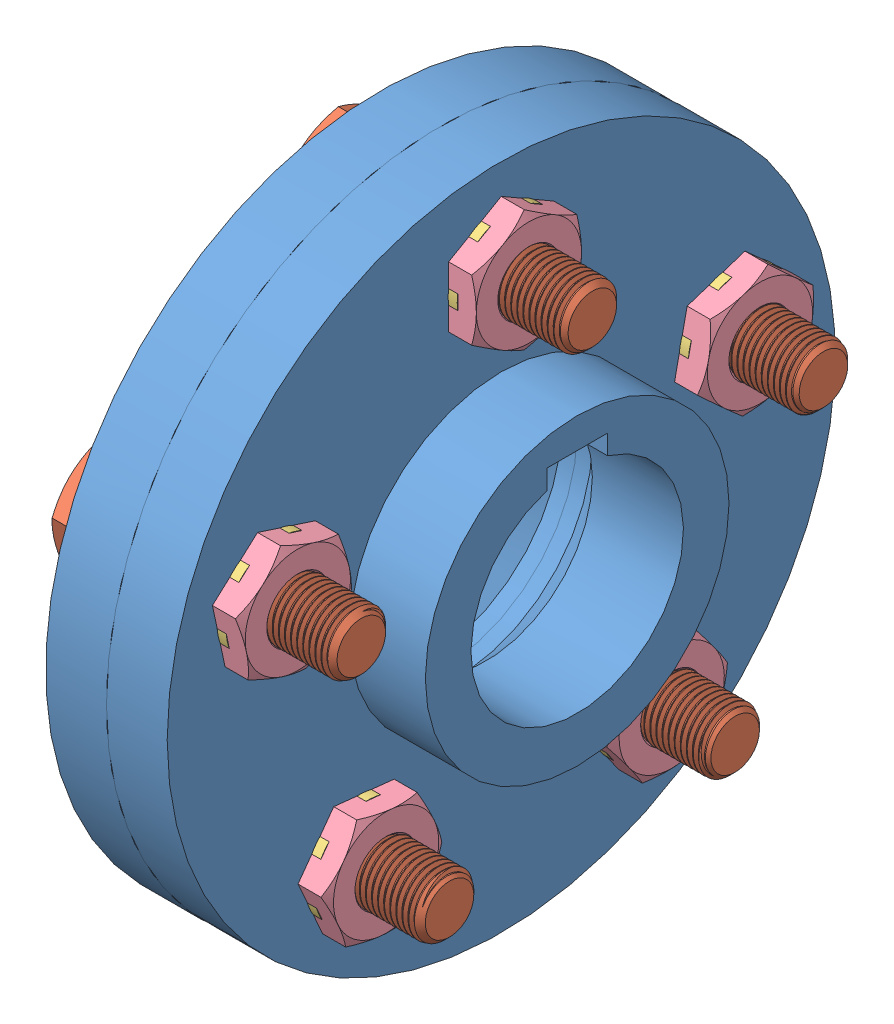
SolidWorks assembly Montaj1, configuration Varsayılan. Lengths in mm.
Overall size (95.08 220 220).
17 component instances, 4 part files, 7 mates.
Components (placement in the parent):
- flange-1: flange [Default] at origin size (45 220 220)
- flange-4: flange [Default] at (-30 0 0) x (-1 0 0) z (0 0 -1) size (45 220 220)
- m20b-1: m20b [Default] at (-35 80 0) x (0 0.448057 0.894005) z (0 -0.894005 0.448057) size (40 84.08 34.64)
- m20w-1: m20w [Default] at (5 80 0) x (0 0.381849 -0.924225) z (0 -0.924225 -0.381849) size (35 3 35)
- m20n-1: m20n [Default] at (6.1117 80 0) x (0 1 0) z (0 0 1) size (40 16 34.64)
- m20n-2: m20n [Default] at (6.1117 24.7214 -76.0845) x (0 0.309017 -0.951057) z (0 0.951057 0.309017) size (40 16 34.64)
- m20n-3: m20n [Default] at (6.1117 -64.7214 -47.0228) x (0 -0.809017 -0.587785) z (0 0.587785 -0.809017) size (40 16 34.64)
- m20n-4: m20n [Default] at (6.1117 -64.7214 47.0228) x (0 -0.809017 0.587785) z (0 -0.587785 -0.809017) size (40 16 34.64)
- m20n-5: m20n [Default] at (6.1117 24.7214 76.0845) x (0 0.309017 0.951057) z (0 -0.951057 0.309017) size (40 16 34.64)
- m20b-2: m20b [Default] at (-35 24.7214 -76.0845) x (0 0.988706 -0.149865) z (0 0.149865 0.988706) size (40 84.08 34.64)
- m20b-3: m20b [Default] at (-35 -64.7214 -47.0228) x (0 0.162997 -0.986627) z (0 0.986627 0.162997) size (40 84.08 34.64)
- m20b-4: m20b [Default] at (-35 -64.7214 47.0228) x (0 -0.887969 -0.459904) z (0 0.459904 -0.887969) size (40 84.08 34.64)
- m20b-5: m20b [Default] at (-35 24.7214 76.0845) x (0 -0.711792 0.70239) z (0 -0.70239 -0.711792) size (40 84.08 34.64)
- m20w-2: m20w [Default] at (5 24.7214 -76.0845) x (0 -0.760992 -0.648761) z (0 -0.648761 0.760992) size (35 3 35)
- m20w-3: m20w [Default] at (5 -64.7214 -47.0228) x (0 -0.852168 0.523268) z (0 0.523268 0.852168) size (35 3 35)
- m20w-4: m20w [Default] at (5 -64.7214 47.0228) x (0 0.234323 0.972159) z (0 0.972159 -0.234323) size (35 3 35)
- m20w-5: m20w [Default] at (5 24.7214 76.0845) x (0 0.996988 0.077559) z (0 0.077559 -0.996988) size (35 3 35)
Mates (geometry in assembly coordinates):
- Eş Merkezli5: concentric anti-aligned: cylinder of flange-1 through (0 0 0) axis (-1 0 0) radius 35; cylinder of flange-4 through (-30 0 0) axis (1 0 0) radius 35
- Çakışık5: coincident anti-aligned: plane of flange-1 through (-15 110 0) normal (-1 0 0); plane of flange-4 through (-15 110 0) normal (1 0 0)
- Çakışık6: coincident anti-aligned: line of flange-1 through (-6.2311 40 10) axis (1 0 0); line of flange-4 through (-23.7689 40 10) axis (-1 0 0)
- Eş Merkezli8: concentric anti-aligned: circle of flange-4; circle of m20b-1
- Çakışık7: coincident anti-aligned: plane of flange-4 through (-35 50 0) normal (-1 0 0); plane of m20b-1 through (-35 80 0) normal (1 0 0)
- Çakışık8: coincident aligned: circle of flange-1; circle of m20w-1
- Eş Merkezli9: concentric anti-aligned: circle of m20w-1; circle of m20n-1
